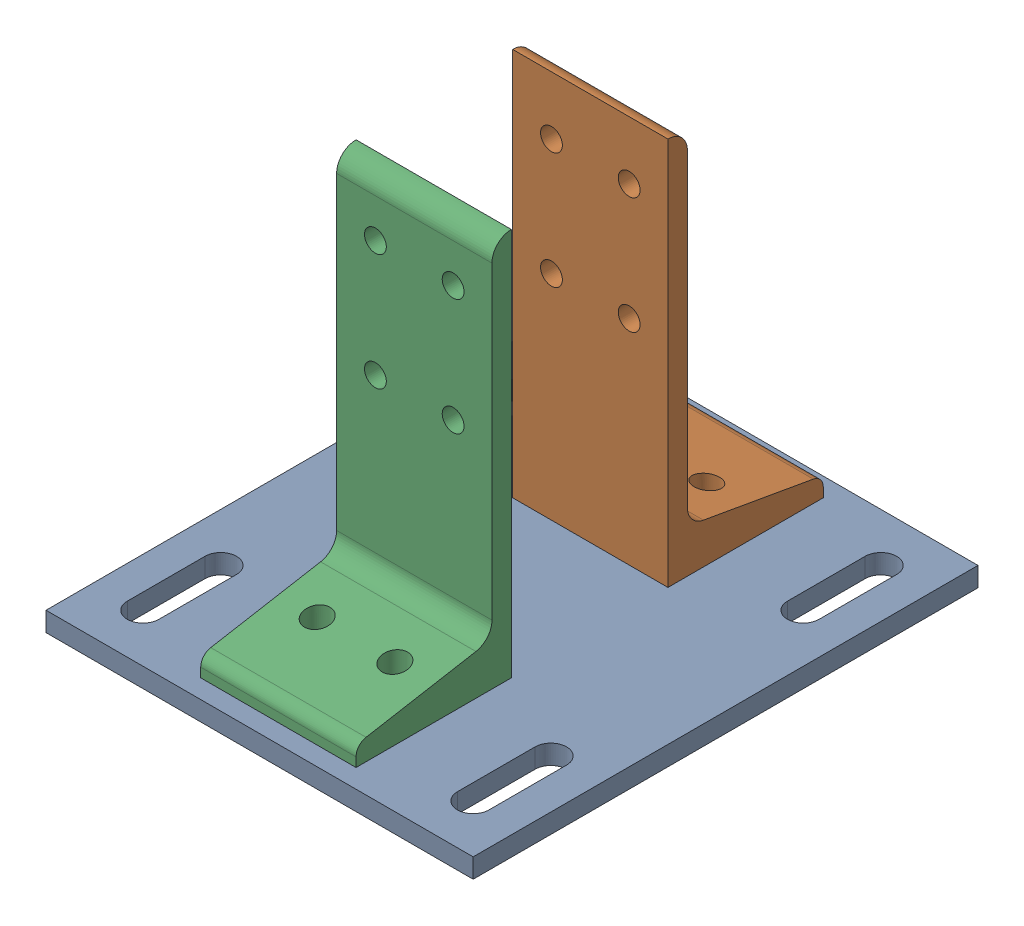
SolidWorks assembly Mirror8020-2387-DEFAULT1, configuration Default. Lengths in mm.
Overall size (139.7 133.35 165.1).
3 component instances, 2 part files, 0 mates.
Components (placement in the parent):
- Mirror8020-2387-DEFAULT_238708-1: Mirror8020-2387-DEFAULT_238708 [Default] at (-67.1549 7.3704 -27.8119) size (139.7 6.35 165.1)
- Mirror8020-2387-DEFAULT_238509-1: Mirror8020-2387-DEFAULT_238509 [Default] at (9.1264 0.0214 -49.7635) x (0 0 -1) z (1 0 0) size (50.8 127 50.8)
- Mirror8020-2387-DEFAULT_238509-2: Mirror8020-2387-DEFAULT_238509 [Default] at (-41.6736 0.0214 46.9187) x (0 0 1) z (-1 0 0) size (50.8 127 50.8)
